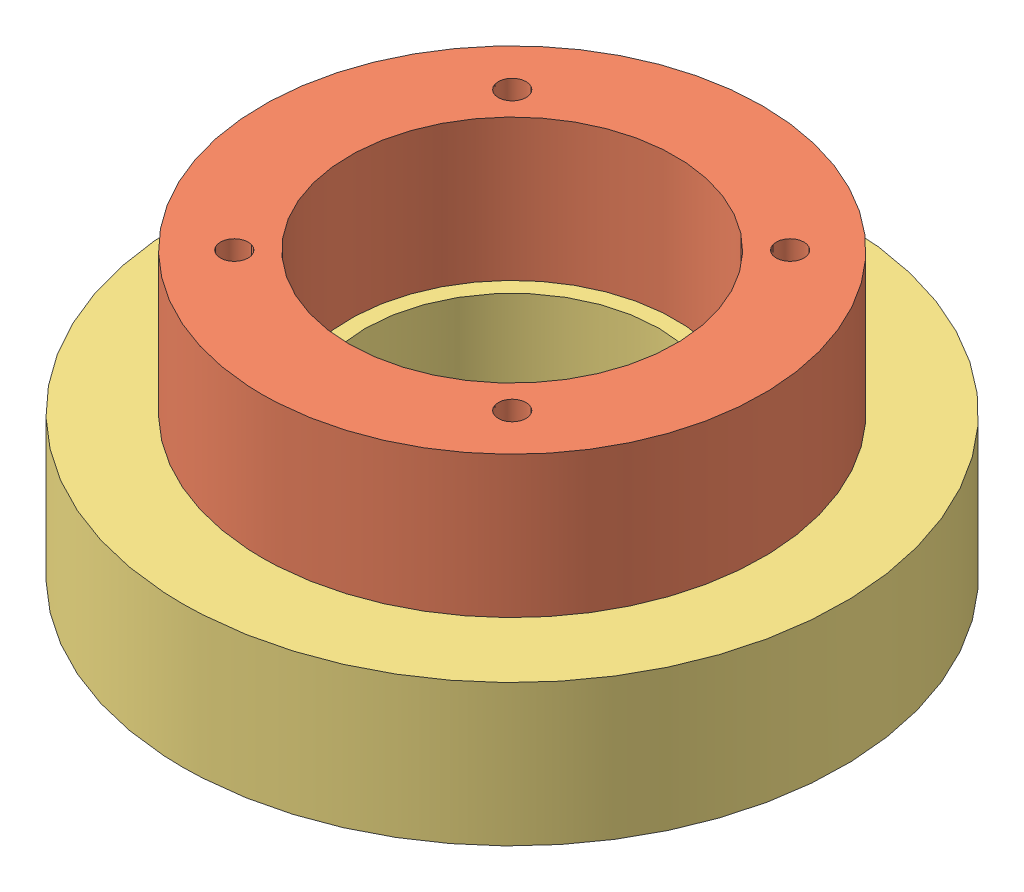
SolidWorks assembly lamp_with_base, configuration Default. Lengths in mm.
Overall size (66.29 28.45 66.29).
3 component instances, 3 part files, 4 mates.
Components (placement in the parent):
- LED_1W-1: LED_1W [Default] at (-12.5919 -11.6616 13.7735) size (20.19 2.34 20.19)
- splitter_bottom-1: splitter_bottom [Default] at (-12.5919 -0.6126 13.7735) size (55.28 14.22 54.8)
- base-1: base [Default] at (-12.5919 -14.8366 13.7735) size (66.29 14.22 66.29)
Mates (geometry in assembly coordinates):
- Coincident1: coincident anti-aligned: plane of LED_1W-1 through (-12.5919 -11.6616 13.7735) normal (0 -1 0); plane of base-1 through (-12.5919 -11.6616 13.7735) normal (0 1 0)
- Concentric1: concentric anti-aligned: circle of LED_1W-1; circle of base-1
- Concentric2: concentric aligned: cylinder of splitter_bottom-1 through (-12.5919 13.6114 13.7735) axis (0 -1 0) radius 25.146; cylinder of base-1 through (-12.5919 -0.6126 13.7735) axis (0 -1 0) radius 33.147
- Coincident2: coincident anti-aligned: plane of splitter_bottom-1 through (-12.5919 -0.6126 13.7735) normal (0 -1 0); plane of base-1 through (-12.5919 -0.6126 13.7735) normal (0 1 0)
